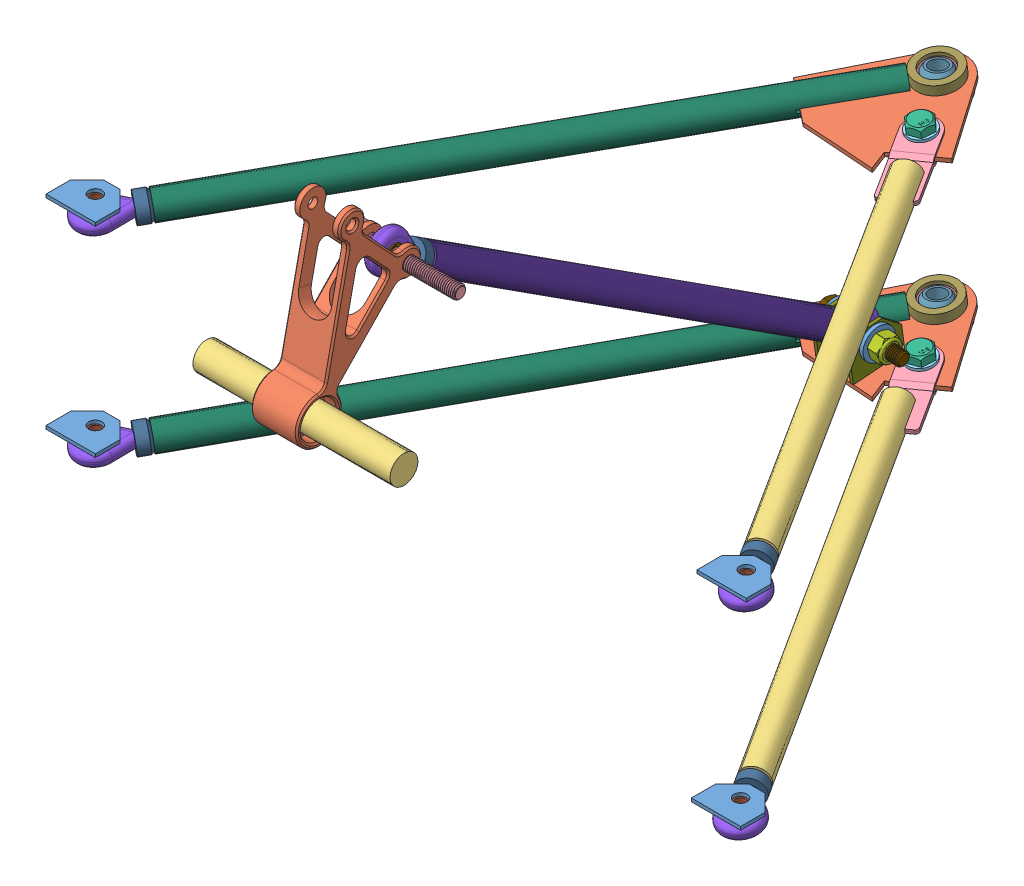
SolidWorks assembly Control Arms, Pushord, Bellcrank V4, configuration Default. Lengths in mm.
Overall size (449.35 304.59 470.75).
69 component instances, 22 part files, 31 mates.
Components (placement in the parent):
- frame connectors-10: frame connectors [Default] at (-357.6393 7.7366 39.1204) size (30 2 25)
- frame connectors-11: frame connectors [Default] at (38.6473 7.7366 39.1204) size (30 2 25)
- Upper Control Arm Assembly-1: Upper Control Arm Assembly [Default] at (-133.4882 -83.0475 -249.6305) x (0.998299 -0.008141 0.057732) z (-0.058303 -0.139388 0.98852) size (425.46 42.68 337.86) (flexible)
  - Front Control Arm Plate-1: Front Control Arm Plate [Default] at origin size (91 2.5 76.52)
  - Rear Upper Control Arm-2: Rear Upper Control Arm [Default] at (102.2777 0 156.6502) x (-0.554844 0 -0.831954) z (0.831954 0 -0.554844) size (250 16 16)
  - Control Arm Link Plate-1: Control Arm Link Plate [Default] at (31.8652 1.25 43.6848) x (-0.554844 0 -0.831954) z (0.831954 0 -0.554844) size (54.1 2.5 20)
  - Control Arm Link Plate-2: Control Arm Link Plate [Default] at (31.8652 -1.25 43.6848) x (-0.554844 0 -0.831954) z (-0.831954 0 0.554844) size (54.1 2.5 20)
  - plain washer normal grade a_iso-1: plain washer normal grade a_iso [Washer ISO 7089 - 8] at (22.4051 2.5 29.5) x (0 -1 0) z (0.774417 0 0.632675) size (1.6 16 16)
  - 94863A205_High-Strength Class 10.9 Steel Hex Head Screw-1: 94863A205_High-Strength Class 10.9 Steel Hex Head Screw [94863A205] at (22.4051 4.1 29.5) x (0.632675 0 -0.774417) z (0 1 0) size (13 16.35 25.89)
  - 94645A111_High-Strength Steel Nylon-Insert Locknut-1: 94645A111_High-Strength Steel Nylon-Insert Locknut [94645A111] at (22.4051 -6.5 29.5) x (-0.772532 0 -0.634976) z (-0.634976 0 0.772532) size (13 8 14.93)
  - Link Insert Assembly-1: Link Insert Assembly [Default] at (147.8527 41.9532 248.8394) x (0.831954 0 -0.554844) z (0 -1 0) size (24 54 13.75) (flexible)
    - Link-1: Link [Default] at (13.2343 18.3157 41.9532) size (24 54 13.75)
    - Spherical Bearing Ball-1: Spherical Bearing Ball [Default] at (13.2343 47.8157 41.9532) x (-0.070566 0.120481 0.990204) z (0.474983 -0.868857 0.139566) size (9 13.75 13.75)
  - Control Arm Insert-1: Control Arm Insert [Default] at (158.7294 0 241.2961) x (-0.831525 0.032128 0.554558) z (0.026729 0.999484 -0.017826) size (16 25 16)
  - 8mm Spehrical Bearing Insert-1: 8mm Spehrical Bearing Insert [Default] at (185.3405 6.4363 280.3709) x (0.945098 -0.03792 -0.32458) z (-0.326686 -0.134378 -0.935531) size (11 9 11)
  - Spherical Bearing Seat-1: Spherical Bearing Seat [Default] at (0 -0.3 0) size (30 15.1 30)
  - Wide Spherical Bearing-1: Wide Spherical Bearing [Default] at (-7.3247 -16.3877 13.3464) x (1 0 0) z (0 1 0) size (27.49 28.27 18.01) (flexible)
    - Wide Bearing Cage-1: Wide Bearing Cage [Default] at (7.3247 13.3464 16.0877) size (22 22 10.5)
    - Wide Ball-1: Wide Ball [Default] at (7.3247 13.3464 16.0877) x (-0.810941 0.567565 -0.142287) z (-0.07098 0.145957 0.986741) size (19.04 19.04 14)
  - Front Upper Control Arm-1: Front Upper Control Arm [Default] at (-100.6334 0 146.8287) x (0.559193 0 -0.829038) z (0.829038 0 0.559193) size (330 16 16)
  - Link Insert Assembly-2: Link Insert Assembly [Default] at (-191.0018 41.9532 257.1385) x (0.829038 0 0.559193) z (0 -1 0) size (24 54 13.75) (flexible)
    - Link-1: Link [Default] at (13.2343 18.3157 41.9532) size (24 54 13.75)
    - Spherical Bearing Ball-1: Spherical Bearing Ball [Default] at (13.2343 47.8157 41.9532) x (0.084694 0.111006 0.990204) z (-0.677269 -0.7225 0.138923) size (9 13.75 13.75)
  - Control Arm Insert-2: Control Arm Insert [Default] at (-179.8953 0 264.3393) x (-0.82861 0.032128 -0.558904) z (0.026635 0.999484 0.017966) size (16 25 16)
  - 8mm Spehrical Bearing Insert-2: 8mm Spehrical Bearing Insert [Default] at (-206.8212 6.4363 303.274) x (-0.994969 -0.02194 -0.097752) z (-0.099853 0.137891 0.985401) size (11 9 11)
  - Push Rod Upper Control Arm Bracket-1: Push Rod Upper Control Arm Bracket [Default] at (10.7762 13.75 44.5) x (0 0 1) z (0 -1 0) size (30 2 25)
  - Push Rod Upper Control Arm Bracket-2: Push Rod Upper Control Arm Bracket [Default] at (-11.2238 13.75 44.5) x (0 0 1) z (0 -1 0) size (30 2 25)
- frame connectors-14: frame connectors [Default] at (-357.6393 -114.2634 39.1204) size (30 2 25)
- frame connectors-15: frame connectors [Default] at (35.1906 -114.2634 39.1204) size (30 2 25)
- Lower Control Arm Assembly-4: Lower Control Arm Assembly [Default] at (-132.0035 38.7923 -248.4945) x (0.997989 -0.008852 0.062774) z (-0.063395 -0.139345 0.988213) size (428.79 25.9 337.86) (flexible)
  - Front Control Arm Plate-1: Front Control Arm Plate [Default] at origin size (91 2.5 76.52)
  - Rear Upper Control Arm-2: Rear Upper Control Arm [Default] at (105.6055 0 154.4308) x (-0.554844 0 -0.831954) z (0.831954 0 -0.554844) size (250 16 16)
  - Control Arm Link Plate-1: Control Arm Link Plate [Default] at (31.8652 1.25 43.6848) x (-0.554844 0 -0.831954) z (0.831954 0 -0.554844) size (54.1 2.5 20)
  - Control Arm Link Plate-2: Control Arm Link Plate [Default] at (31.8652 -1.25 43.6848) x (-0.554844 0 -0.831954) z (-0.831954 0 0.554844) size (54.1 2.5 20)
  - plain washer normal grade a_iso-1: plain washer normal grade a_iso [Washer ISO 7089 - 8] at (22.4051 2.5 29.5) x (0 -1 0) z (0.774417 0 0.632675) size (1.6 16 16)
  - 94863A205_High-Strength Class 10.9 Steel Hex Head Screw-1: 94863A205_High-Strength Class 10.9 Steel Hex Head Screw [94863A205] at (22.4051 4.1 29.5) x (0.632675 0 -0.774417) z (0 1 0) size (13 16.35 25.89)
  - 94645A111_High-Strength Steel Nylon-Insert Locknut-1: 94645A111_High-Strength Steel Nylon-Insert Locknut [94645A111] at (22.4051 -6.5 29.5) x (-0.783807 0 -0.621005) z (-0.621005 0 0.783807) size (13 8 14.93)
  - Link Insert Assembly-1: Link Insert Assembly [Default] at (151.1806 41.9532 246.62) x (0.831954 0 -0.554844) z (0 -1 0) size (24 54 13.75) (flexible)
    - Link-1: Link [Default] at (13.2343 18.3157 41.9532) size (24 54 13.75)
    - Spherical Bearing Ball-1: Spherical Bearing Ball [Default] at (13.2343 47.8157 41.9532) x (-0.069951 0.12084 0.990204) z (-0.21851 0.966673 -0.133404) size (9 13.75 13.75)
  - Control Arm Insert-1: Control Arm Insert [Default] at (162.0573 0 239.0767) x (-0.831525 0.032128 0.554558) z (0.026729 0.999484 -0.017826) size (16 25 16)
  - 8mm Spehrical Bearing Insert-1: 8mm Spehrical Bearing Insert [Default] at (188.6637 6.4363 278.1518) x (0.571329 0.119373 0.811993) z (0.820673 -0.072424 -0.566789) size (11 9 11)
  - Spherical Bearing Seat-1: Spherical Bearing Seat [Default] at (0 -0.3 0) size (30 15.1 30)
  - Wide Spherical Bearing-1: Wide Spherical Bearing [Default] at (-7.3247 -16.3877 13.3464) x (1 0 0) z (0 1 0) size (27.03 27.79 18.09) (flexible)
    - Wide Bearing Cage-1: Wide Bearing Cage [Default] at (7.3247 13.3464 16.0877) size (22 22 10.5)
    - Wide Ball-1: Wide Ball [Default] at (7.3247 13.3464 16.0877) x (-0.856962 0.497351 -0.135121) z (-0.070956 0.145825 0.986762) size (19.04 19.04 14)
  - Front Upper Control Arm-1: Front Upper Control Arm [Default] at (-100.6334 0 146.8287) x (0.559193 0 -0.829038) z (0.829038 0 0.559193) size (330 16 16)
  - Link Insert Assembly-2: Link Insert Assembly [Default] at (-191.0018 41.9532 257.1385) x (0.829038 0 0.559193) z (0 -1 0) size (24 54 13.75) (flexible)
    - Link-1: Link [Default] at (13.2343 18.3157 41.9532) size (24 54 13.75)
    - Spherical Bearing Ball-1: Spherical Bearing Ball [Default] at (13.2343 47.8157 41.9532) x (0.085259 0.110572 0.990204) z (-0.741155 -0.657165 0.137198) size (9 13.75 13.75)
  - Control Arm Insert-2: Control Arm Insert [Default] at (-179.8953 0 264.3393) x (-0.82861 0.032128 -0.558904) z (0.026635 0.999484 0.017966) size (16 25 16)
  - 8mm Spehrical Bearing Insert-2: 8mm Spehrical Bearing Insert [Default] at (-206.8258 6.4363 303.2743) x (-0.997188 -0.019112 -0.072467) z (-0.07442 0.138311 0.987589) size (11 9 11)
- Front Push Rod Assembly-1: Front Push Rod Assembly [Default] at (-341.9805 -78.1784 123.7798) x (-0.000009 -0.541562 -0.840661) z (1 -0.000016 0) size (363.6 24 20.9) (flexible)
  - Front Push Rod-1: Front Push Rod [Default] at (102.5362 181.4229 205.1752) size (290 16 16)
  - Control Arm Insert-1: Control Arm Insert [Default] at (224.2796 181.4229 205.1752) x (0 -1 0) z (0 0 1) size (16 25 16)
  - Control Arm Insert-2: Control Arm Insert [Default] at (-19.2072 181.4229 205.1752) x (0 -0.381849 0.924225) z (0 -0.924225 -0.381849) size (16 25 16)
  - Link Insert Assembly-1: Link Insert Assembly [Default] at (-19.4481 168.1886 163.222) x (0 1 0) z (0 0 1) size (24 54 13.75) (flexible)
    - Link-1: Link [Default] at (13.2343 18.3157 41.9532) size (24 54 13.75)
    - Spherical Bearing Ball-1: Spherical Bearing Ball [Default] at (13.2343 47.8157 41.9532) x (0 0 1) z (-0.941942 0.335775 0) size (9 13.75 13.75)
  - Link Insert Assembly-2: Link Insert Assembly [Default] at (224.5204 194.6572 163.222) x (0 -1 0) z (0 0 1) size (24 54 13.75) (flexible)
    - Link-1: Link [Default] at (13.2343 18.3157 41.9532) size (24 54 13.75)
    - Spherical Bearing Ball-1: Spherical Bearing Ball [Default] at (13.2343 47.8157 41.9532) x (0.038095 -0.044133 0.998299) z (0.938598 -0.341238 -0.050902) size (9 13.75 13.75)
- M8 45mm hex bolt-1: M8 45mm hex bolt [91310A132] at (-131.2946 -73.1985 -203.0956) x (0.037825 -0.663102 -0.747573) z (-0.998299 0.008141 -0.057732) size (13 14.81 50.91)
- flat washer narrow_am-1: flat washer narrow_am [B18.22M - Plain washer, 8 mm, narrow] at (-148.2857 -73.06 -204.0782) x (0.998299 -0.008141 0.057732) z (-0.058266 -0.17424 0.982978) size (2.3 18.8 18.8)
- Bell Crank-1: Bell Crank [Default] at (-137.8032 54.6894 136.2957) x (0.000012 0.730821 0.682569) z (-0.000011 -0.682569 0.730821) size (76.38 28 99.9)
- FRAME ROD-1: FRAME ROD [Default] at (-132.5443 54.6893 136.2957) x (0 0.036214 0.999344) z (-1 0.000016 0) size (17 17 120)
- 94645A111_High-Strength Steel Nylon-Insert Locknut-1: 94645A111_High-Strength Steel Nylon-Insert Locknut [94645A111] at (-118.0372 -73.3066 -202.3289) x (0.057199 0.328515 -0.942765) z (0.011291 -0.944464 -0.328421) size (13 8 14.93)
- flat washer narrow_am-3: flat washer narrow_am [B18.22M - Plain washer, 8 mm, narrow] at (-122.0304 -73.2741 -202.5598) x (0.998299 -0.008141 0.057732) z (-0.058266 -0.17424 0.982978) size (2.3 18.8 18.8)
- M8x1.25 60mm hex bolt-3: M8x1.25 60mm hex bolt [91310A545] at (-124.9823 110.7607 82.0741) x (0.000014 0.851832 0.523815) z (-1 0.000016 0) size (13 14.81 66)
Mates (geometry in assembly coordinates):
- Concentric18: concentric aligned: cylinder of frame connectors-10 through (-357.6393 8.7366 39.1204) axis (0 -1 0) radius 4; cylinder of frame connectors-14 through (-357.6393 -113.2634 39.1204) axis (0 -1 0) radius 4
- Coincident27: coincident aligned: plane of frame connectors-10 through (-372.6393 8.7366 54.1204) normal (0 0 1); plane of frame connectors-14 through (-372.6393 -113.2634 54.1204) normal (0 0 1)
- Distance2: distance = 120 mm anti-aligned: plane of frame connectors-14 through (-357.6393 -113.2634 39.1204) normal (0 1 0); plane of frame connectors-10 through (-357.6393 6.7366 39.1204) normal (0 -1 0)
- Concentric19: concentric aligned: cylinder of Upper Control Arm Assembly-1/8mm Spehrical Bearing Insert-2 through (-357.6393 -117.2634 39.1204) axis (0 -1 0) radius 3; cylinder of frame connectors-14 through (-357.6393 -113.2634 39.1204) axis (0 -1 0) radius 4
- Coincident29: coincident anti-aligned: plane of Upper Control Arm Assembly-1/8mm Spehrical Bearing Insert-2 through (-352.2076 -115.2634 39.9847) normal (0 1 0); plane of frame connectors-14 through (-357.6393 -115.2634 39.1204) normal (0 -1 0)
- Coincident30: coincident aligned: plane of frame connectors-14 through (-372.6393 -113.2634 54.1204) normal (0 0 1); plane of frame connectors-15 through (20.1906 -113.2634 54.1204) normal (0 0 1)
- Coincident31: coincident aligned: plane of frame connectors-14 through (-357.6393 -113.2634 39.1204) normal (0 1 0); plane of frame connectors-15 through (35.1906 -113.2634 39.1204) normal (0 1 0)
- Concentric21: concentric aligned: cylinder of frame connectors-10 through (-357.6393 8.7366 39.1204) axis (0 -1 0) radius 4; circle of Lower Control Arm Assembly-4/8mm Spehrical Bearing Insert-2
- Coincident33: coincident anti-aligned: plane of frame connectors-10 through (-357.6393 6.7366 39.1204) normal (0 -1 0); plane of Lower Control Arm Assembly-4/8mm Spehrical Bearing Insert-2 through (-352.191 6.7366 39.8732) normal (0 1 0)
- Coincident38: coincident anti-aligned: plane of Upper Control Arm Assembly-1/8mm Spehrical Bearing Insert-1 through (29.8973 -115.2634 40.6141) normal (0 1 0); plane of frame connectors-15 through (35.1906 -115.2634 39.1204) normal (0 -1 0)
- Concentric22: concentric aligned: cylinder of Upper Control Arm Assembly-1/8mm Spehrical Bearing Insert-1 through (35.1906 -117.2634 39.1204) axis (0 -1 0) radius 3; cylinder of frame connectors-15 through (35.1906 -113.2634 39.1204) axis (0 -1 0) radius 4
- Coincident39: coincident aligned: plane of frame connectors-10 through (-372.6393 8.7366 54.1204) normal (0 0 1); plane of frame connectors-11 through (23.6473 8.7366 54.1204) normal (0 0 1)
- Coincident40: coincident aligned: plane of frame connectors-10 through (-357.6393 8.7366 39.1204) normal (0 1 0); plane of frame connectors-11 through (38.6473 8.7366 39.1204) normal (0 1 0)
- Concentric23: concentric aligned: cylinder of frame connectors-11 through (38.6473 8.7366 39.1204) axis (0 -1 0) radius 4; cylinder of Lower Control Arm Assembly-4/8mm Spehrical Bearing Insert-1 through (38.6473 4.7366 39.1204) axis (0 -1 0) radius 3
- Coincident41: coincident anti-aligned: plane of frame connectors-11 through (38.6473 6.7366 39.1204) normal (0 -1 0); plane of Lower Control Arm Assembly-4/8mm Spehrical Bearing Insert-1 through (35.7944 6.7366 34.4182) normal (0 1 0)
- Parallel9: parallel aligned: plane of Upper Control Arm Assembly-1/Front Control Arm Plate-1 through (-133.4872 -81.8075 -249.4724) normal (0 0.990204 0.139626); plane of Lower Control Arm Assembly-4/Front Control Arm Plate-1 through (-132.0025 40.0323 -248.3363) normal (0 0.990204 0.139626)
- Concentric24: concentric anti-aligned: cylinder of Upper Control Arm Assembly-1/Push Rod Upper Control Arm Bracket-2 through (-148.2857 -73.06 -204.0782) axis (0.998299 -0.008141 0.057732) radius 4; cylinder of flat washer narrow_am-1 through (-183.1513 -72.7757 -206.0945) axis (-0.998299 0.008141 -0.057732) radius 4.56
- Coincident42: coincident anti-aligned: plane of Upper Control Arm Assembly-1/Push Rod Upper Control Arm Bracket-2 through (-148.2857 -75.5355 -204.4272) normal (-0.998299 0.008141 -0.057732); plane of flat washer narrow_am-1 through (-148.2951 -68.5699 -203.2828) normal (0.998299 -0.008141 0.057732)
- Concentric25: concentric anti-aligned: cylinder of Upper Control Arm Assembly-1/Push Rod Upper Control Arm Bracket-2 through (-148.2857 -73.06 -204.0782) axis (0.998299 -0.008141 0.057732) radius 4; cylinder of M8 45mm hex bolt-1 through (-151.1109 -73.0369 -204.2416) axis (-0.998299 0.008141 -0.057732) radius 5.7528
- Coincident43: coincident anti-aligned: plane of M8 45mm hex bolt-1 through (-150.5818 -73.0412 -204.211) normal (0.998299 -0.008141 0.057732); plane of flat washer narrow_am-1 through (-150.6011 -63.7854 -202.5714) normal (-0.998299 0.008141 -0.057732)
- Concentric26: concentric aligned: cylinder of Front Push Rod Assembly-1/Link Insert Assembly-2/Spherical Bearing Ball-1 through (-143.6703 -73.0976 -203.8113) axis (-0.998299 0.008141 -0.057732) radius 4; cylinder of M8 45mm hex bolt-1 through (-151.1109 -73.0369 -204.2416) axis (-0.998299 0.008141 -0.057732) radius 5.7528
- Distance3: distance = 6 mm anti-aligned: plane of Front Push Rod Assembly-1/Link Insert Assembly-2/Spherical Bearing Ball-1 through (-132.4606 -69.0471 -200.0156) normal (0.998299 -0.008141 0.057732); plane of Upper Control Arm Assembly-1/Push Rod Upper Control Arm Bracket-1 through (-126.3231 -75.7146 -203.1571) normal (-0.998299 0.008141 -0.057732)
- Concentric28: concentric aligned: cylinder of Front Push Rod Assembly-1/Link Insert Assembly-1/Spherical Bearing Ball-1 through (-143.679 110.761 82.0741) axis (-1 0.000016 0) radius 4; cylinder of Bell Crank-1 through (-123.8023 110.7607 82.0741) axis (-1 0.000016 0) radius 3
- Distance4: distance = 7 mm anti-aligned: plane of Front Push Rod Assembly-1/Link Insert Assembly-1/Link-1 through (-140.8023 110.761 82.0741) normal (-1 0.000016 0); plane of Bell Crank-1 through (-147.8019 130.8521 48.8423) normal (1 -0.000016 0)
- Concentric35: concentric anti-aligned: cylinder of Bell Crank-1 through (-123.8032 54.6891 136.2957) axis (-1 0.000016 0) radius 8.5; cylinder of FRAME ROD-1 through (-192.5443 54.6902 136.2957) axis (1 -0.000016 0) radius 8.5
- Concentric36: concentric aligned: cylinder of M8 45mm hex bolt-1 through (-151.1109 -73.0369 -204.2416) axis (-0.998299 0.008141 -0.057732) radius 5.7528; cylinder of 94645A111_High-Strength Steel Nylon-Insert Locknut-1 through (-122.0304 -73.2741 -202.5598) axis (-0.998299 0.008141 -0.057732) radius 6.5
- Concentric37: concentric aligned: cylinder of M8 45mm hex bolt-1 through (-151.1109 -73.0369 -204.2416) axis (-0.998299 0.008141 -0.057732) radius 5.7528; cylinder of flat washer narrow_am-3 through (-156.896 -72.9898 -204.5761) axis (-0.998299 0.008141 -0.057732) radius 4.56
- Coincident56: coincident anti-aligned: plane of Upper Control Arm Assembly-1/Push Rod Upper Control Arm Bracket-1 through (-124.3265 -75.7309 -203.0417) normal (0.998299 -0.008141 0.057732); plane of flat washer narrow_am-3 through (-124.3458 -63.9995 -201.0531) normal (-0.998299 0.008141 -0.057732)
- Coincident57: coincident anti-aligned: plane of 94645A111_High-Strength Steel Nylon-Insert Locknut-1 through (-122.0304 -73.2741 -202.5598) normal (-0.998299 0.008141 -0.057732); plane of flat washer narrow_am-3 through (-122.0398 -68.784 -201.7645) normal (0.998299 -0.008141 0.057732)
- Concentric39: concentric aligned: cylinder of Front Push Rod Assembly-1/Link Insert Assembly-1/Spherical Bearing Ball-1 through (-143.679 110.761 82.0741) axis (-1 0.000016 0) radius 4; cylinder of M8x1.25 60mm hex bolt-3 through (-152.3323 110.7612 82.0741) axis (-1 0.000016 0) radius 5.7528
- Coincident58: coincident anti-aligned: plane of Bell Crank-1 through (-151.8032 54.6896 136.2957) normal (-1 0.000016 0); plane of M8x1.25 60mm hex bolt-3 through (-151.8023 110.7612 82.0741) normal (1 -0.000016 0)
